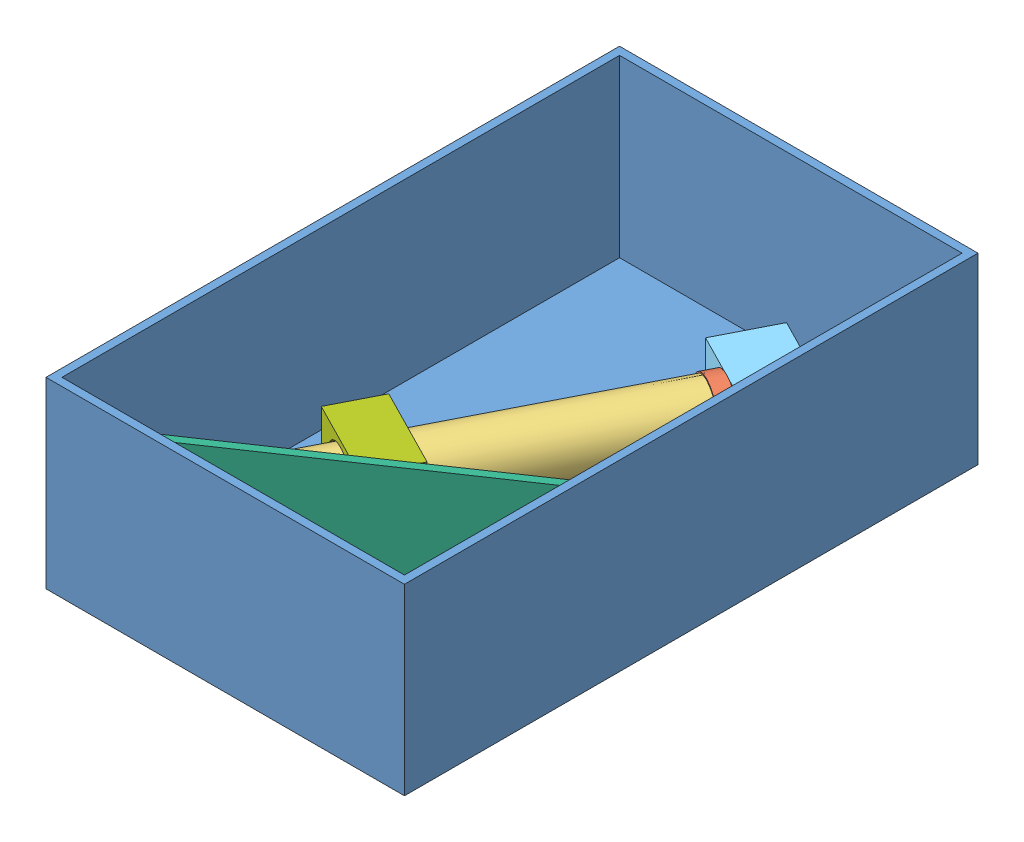
SolidWorks assembly Assembly, configuration Default. Lengths in mm.
Overall size (142.88 99.85 228.6).
9 component instances, 8 part files, 12 mates.
Components (placement in the parent):
- Basic-ForSizing-1: Basic-ForSizing [Default] at (85.866 92.106 126.5349) size (142.88 73.02 228.6)
- auger-1: auger [Default] at (131.7954 117.106 108.8621) x (-0.890852 0 -0.454294) z (0 1 0) size (25.4 178.38 25.4)
- tube-1: tube [Default] at (51.8395 117.106 265.652) x (-0.863065 0.247808 -0.440125) z (-0.22076 -0.968809 -0.112578) size (24.38 170 24.38)
- stepper_holder-1: stepper_holder [Default] at (132.9848 63.1832 148.8831) x (-0.890852 0 -0.454294) z (0.454294 0 -0.890852) size (48 64 31.52)
  - Step Motor (28BYJ-48)-1: Step Motor (28BYJ-48) [Varsayılan] at (19.2409 45.9228 39.1125) size (42 61 29.02)
  - stepper_holder_28BYJ-48-1: stepper_holder_28BYJ-48 [Default] at (19.2409 28.9228 46.0671) size (48 34 24)
- slope-1: slope [Default] at (93.2243 110.271 258.2882) x (0.828262 0 -0.560341) z (0 1 0) size (120 3.17 66.67)
- face-1: face [Default] at (34.5446 158.781 55.0022) size (136.52 3.17 222.25) (hidden)
- auger_holder-1: auger_holder [Default] at (83.684 92.106 200.6427) x (0.890852 0 0.454294) z (-0.454294 0 0.890852) size (35 40 20)
Mates (geometry in assembly coordinates):
- Concentric1: concentric anti-aligned: circle of auger-1; circle of tube-1
- Coincident5: coincident anti-aligned: plane of auger-1 through (129.0696 117.106 114.2072) normal (-0.454294 0 0.890852); plane of tube-1 through (129.0696 117.106 114.2072) normal (0.454294 0 -0.890852)
- Coincident6: coincident anti-aligned: plane of Basic-ForSizing-1 through (85.866 92.106 126.5349) normal (0 1 0); plane of stepper_holder-1/stepper_holder_28BYJ-48-1 through (136.772 92.106 99.1031) normal (0 -1 0)
- Coincident7: coincident anti-aligned: plane of auger-1 through (129.0696 117.106 114.2072) normal (0.454294 0 -0.890852); plane of stepper_holder-1/Step Motor (28BYJ-48)-1 through (129.0696 117.106 114.2072) normal (-0.454294 0 0.890852)
- Coincident8: coincident anti-aligned: plane of auger-1 through (131.2967 118.606 115.3429) normal (0 -1 0); plane of stepper_holder-1/Step Motor (28BYJ-48)-1 through (127.2879 118.606 113.2986) normal (0 1 0)
- Concentric2: concentric aligned: cylinder of auger-1 through (129.0696 117.106 114.2072) axis (0.454294 0 -0.890852) radius 12.7; circle of stepper_holder-1/Step Motor (28BYJ-48)-1
- Coincident10: coincident anti-aligned: plane of Basic-ForSizing-1 through (85.866 92.106 126.5349) normal (0 1 0); plane of slope-1 through (67.6718 92.106 271.7418) normal (0 -1 0)
- Coincident11: coincident: plane of Basic-ForSizing-1 through (32.3173 161.956 274.3715) normal (0 0 -1); line of slope-1 through (69.4509 92.106 274.3715) axis (0 1 0)
- Coincident12: coincident: plane of Basic-ForSizing-1 through (168.8423 161.956 52.1215) normal (-1 0 0); line of slope-1 through (168.8423 158.781 207.1306) axis (0 -1 0)
- Coincident13: coincident anti-aligned: plane of slope-1 through (67.6718 158.781 271.7418) normal (0 1 0); plane of face-1 through (34.5446 158.781 55.0022) normal (0 -1 0)
- Coincident15: coincident: point of Basic-ForSizing-1; point of face-1
- Concentric6: concentric aligned: cylinder of tube-1 through (129.0696 117.106 114.2072) axis (-0.454294 0 0.890852) radius 12.192; cylinder of auger_holder-1 through (88.876 117.106 193.0251) axis (-0.454294 0 0.890852) radius 12.7
